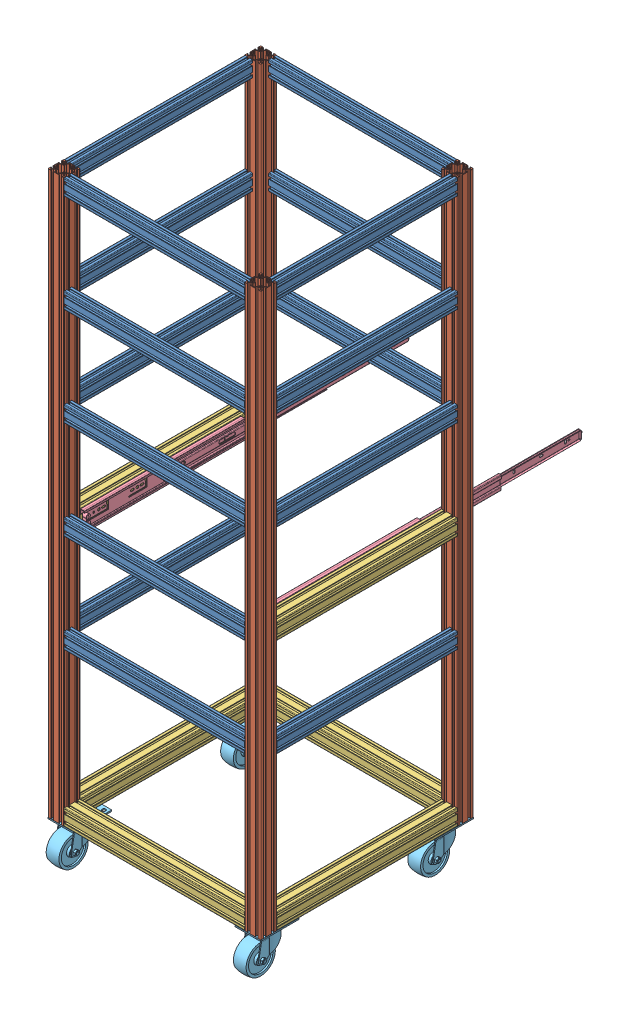
SolidWorks assembly Frame V4, configuration Default. Lengths in mm.
Overall size (530 1495.25 868.67).
34 component instances, 5 part files, 61 mates.
Components (placement in the parent):
- Frame V3 Front_or_Back-1: Frame V3 Front_or_Back [Default] at (-126.3106 303.3726 1707.2815) size (40 1400 530)
  - 20_2040_450_CL-1: 20_2040_450_CL [Default] at (841.1716 1609.6814 362.4928) size (20 40 450)
  - 20_2040_450_CL-2: 20_2040_450_CL [Default] at (841.1716 1364.9814 362.4928) size (20 40 450)
  - 20_2040_450_CL-3: 20_2040_450_CL [Default] at (841.1716 1120.2814 362.4928) size (20 40 450)
  - 20_4040_1400_CL-1: 20_4040_1400_CL [Default] at (851.1716 239.6814 372.4928) x (1 0 0) z (0 -1 0) size (40 40 1400)
  - 20_4040_1400_CL-2: 20_4040_1400_CL [Default] at (851.1716 239.6814 -117.5072) x (1 0 0) z (0 -1 0) size (40 40 1400)
  - 20_2040_450_CL-5: 20_2040_450_CL [Default] at (841.1716 630.8814 362.4928) size (20 40 450)
  - 20_4040_450_CL-1: 20_4040_450_CL [Default] at (851.1716 875.5814 362.4928) size (40 40 450)
- Frame V3 Front_or_Back-2: Frame V3 Front_or_Back [Default] at (2066.0326 303.3726 1982.2671) x (-1 0 0) z (0 0 -1) size (40 1400 530)
  - 20_2040_450_CL-1: 20_2040_450_CL [Default] at (841.1716 1609.6814 362.4928) size (20 40 450)
  - 20_2040_450_CL-2: 20_2040_450_CL [Default] at (841.1716 1364.9814 362.4928) size (20 40 450)
  - 20_2040_450_CL-3: 20_2040_450_CL [Default] at (841.1716 1120.2814 362.4928) size (20 40 450)
  - 20_4040_1400_CL-1: 20_4040_1400_CL [Default] at (851.1716 239.6814 372.4928) x (1 0 0) z (0 -1 0) size (40 40 1400)
  - 20_4040_1400_CL-2: 20_4040_1400_CL [Default] at (851.1716 239.6814 -117.5072) x (1 0 0) z (0 -1 0) size (40 40 1400)
  - 20_2040_450_CL-5: 20_2040_450_CL [Default] at (841.1716 630.8814 362.4928) size (20 40 450)
  - 20_4040_450_CL-1: 20_4040_450_CL [Default] at (851.1716 875.5814 362.4928) size (40 40 450)
- 20_2040_450_CL-1: 20_2040_450_CL [Default] at (1194.861 1913.054 2099.7743) x (0 0 -1) z (1 0 0) size (20 40 450)
- 20_2040_450_CL-2: 20_2040_450_CL [Default] at (1194.861 1913.054 1589.7743) x (0 0 -1) z (1 0 0) size (20 40 450)
- 20_4040_450_CL-1: 20_4040_450_CL [Default] at (1214.861 553.054 2069.7743) size (40 40 450)
- 20_4040_450_CL-2: 20_4040_450_CL [Default] at (724.861 553.054 2069.7743) size (40 40 450)
- 20_2040_450_CL-3: 20_2040_450_CL [Default] at (1194.861 1668.354 2099.7743) x (0 0 -1) z (1 0 0) size (20 40 450)
- 20_2040_450_CL-4: 20_2040_450_CL [Default] at (1194.861 1423.654 2099.7743) x (0 0 -1) z (1 0 0) size (20 40 450)
- 20_4040_450_CL-3: 20_4040_450_CL [Default] at (1194.861 553.054 2089.7743) x (0 0 -1) z (1 0 0) size (40 40 450)
- 20_4040_450_CL-4: 20_4040_450_CL [Default] at (1194.861 553.054 1599.7743) x (0 0 -1) z (1 0 0) size (40 40 450)
- 20_2040_450_CL-5: 20_2040_450_CL [Default] at (1194.861 1178.954 2099.7743) x (0 0 -1) z (1 0 0) size (20 40 450)
- 20_2040_450_CL-6: 20_2040_450_CL [Default] at (1194.861 934.254 2099.7743) x (0 0 -1) z (1 0 0) size (20 40 450)
- 20_2040_450_CL-7: 20_2040_450_CL [Default] at (1194.861 1668.354 1589.7743) x (0 0 -1) z (1 0 0) size (20 40 450)
- 20_2040_450_CL-8: 20_2040_450_CL [Default] at (1194.861 1423.654 1589.7743) x (0 0 -1) z (1 0 0) size (20 40 450)
- 11435A14_Steel Drawer Slides-3: 11435A14_Steel Drawer Slides [11435A14] at (1187.9155 1186.2842 1663.3743) x (-0.999657 0.026177 0) z (0 0 1) size (12.7 45.64 806.45)
- 11435A14_Steel Drawer Slides-4: 11435A14_Steel Drawer Slides [11435A14] at (751.8049 1186.2842 1663.3743) x (0.999657 0.026177 0) z (0 0 1) size (12.7 45.64 806.45)
- 2358T21_Static-Control Plate Caster-1: 2358T21_Static-Control Plate Caster [2358T21] at (736.611 485.904 2093.8993) size (63.5 95.25 117.47)
- 2358T21_Static-Control Plate Caster-2: 2358T21_Static-Control Plate Caster [2358T21] at (1203.111 485.904 2093.8993) size (63.5 95.25 117.47)
- 2358T21_Static-Control Plate Caster-3: 2358T21_Static-Control Plate Caster [2358T21] at (1203.111 485.904 1659.1493) size (63.5 95.25 117.47)
- 2358T21_Static-Control Plate Caster-4: 2358T21_Static-Control Plate Caster [2358T21] at (736.611 485.904 1659.1493) size (63.5 95.25 117.47)
Mates (geometry in assembly coordinates):
- Coincident16: coincident anti-aligned: plane of Frame V3 Front_or_Back-1/40_4040_1400_CL-1 through (946.4642 1867.0428 2134.8899) normal (1 0 0); plane of 20_2040_450_CL-1 through (744.861 1941.554 2108.2743) normal (-1 0 0)
- Coincident17: coincident aligned: plane of Frame V3 Front_or_Back-1/40_4040_1400_CL-1 through (943.2942 1867.0428 2149.1994) normal (0 0 1); plane of 20_2040_450_CL-1 through (744.861 1929.916 2109.7743) normal (0 0 1)
- Coincident18: coincident aligned: plane of Frame V3 Front_or_Back-1/40_4040_1400_CL-1 through (909.6342 1867.0428 2146.0294) normal (0 1 0); plane of 20_2040_450_CL-1 through (744.861 1943.054 2102.9123) normal (0 1 0)
- Coincident21: coincident: plane of Frame V3 Front_or_Back-1/40_4040_1400_CL-2 through (946.4642 1867.0428 1622.3694) normal (1 0 0); plane of 20_2040_450_CL-2 through (744.861 1941.554 1598.2743) normal (-1 0 0)
- Coincident22: coincident: plane of Frame V3 Front_or_Back-1/40_4040_1400_CL-2 through (932.1546 1867.0428 1619.1994) normal (0 0 -1); plane of 20_2040_450_CL-2 through (744.861 1916.192 1579.7743) normal (0 0 -1)
- Coincident23: coincident aligned: plane of Frame V3 Front_or_Back-2/40_4040_1400_CL-1 through (1433.2942 1867.0428 1622.3694) normal (0 1 0); plane of 20_2040_450_CL-2 through (744.861 1943.054 1581.2743) normal (0 1 0)
- Coincident24: coincident anti-aligned: plane of Frame V3 Front_or_Back-1/20_4040_1400_CL-1 through (744.861 1943.054 2082.9123) normal (1 0 0); plane of 20_2040_450_CL-1 through (744.861 1941.554 2108.2743) normal (-1 0 0)
- Coincident25: coincident aligned: plane of Frame V3 Front_or_Back-1/20_4040_1400_CL-1 through (731.723 1943.054 2109.7743) normal (0 0 1); plane of 20_2040_450_CL-1 through (744.861 1929.916 2109.7743) normal (0 0 1)
- Coincident26: coincident aligned: plane of Frame V3 Front_or_Back-1/20_4040_1400_CL-1 through (706.361 1943.054 2108.2743) normal (0 1 0); plane of 20_2040_450_CL-1 through (744.861 1943.054 2102.9123) normal (0 1 0)
- Coincident27: coincident anti-aligned: plane of Frame V3 Front_or_Back-1/20_4040_1400_CL-2 through (744.861 1943.054 1592.9123) normal (1 0 0); plane of 20_2040_450_CL-2 through (744.861 1941.554 1598.2743) normal (-1 0 0)
- Coincident28: coincident aligned: plane of Frame V3 Front_or_Back-1/20_4040_1400_CL-2 through (717.999 1943.054 1579.7743) normal (0 0 -1); plane of 20_2040_450_CL-2 through (744.861 1916.192 1579.7743) normal (0 0 -1)
- Coincident29: coincident aligned: plane of Frame V3 Front_or_Back-1/20_4040_1400_CL-2 through (706.361 1943.054 1618.2743) normal (0 1 0); plane of 20_2040_450_CL-2 through (744.861 1943.054 1581.2743) normal (0 1 0)
- Coincident30: coincident anti-aligned: plane of Frame V3 Front_or_Back-2/20_4040_1400_CL-2 through (1194.861 1943.054 2096.6363) normal (-1 0 0); plane of 20_2040_450_CL-1 through (1194.861 1941.554 2108.2743) normal (1 0 0)
- Coincident31: coincident aligned: plane of Frame V3 Front_or_Back-2/20_4040_1400_CL-2 through (1233.361 1943.054 2071.2743) normal (0 1 0); plane of 20_2040_450_CL-1 through (744.861 1943.054 2102.9123) normal (0 1 0)
- Coincident32: coincident aligned: plane of Frame V3 Front_or_Back-2/20_4040_1400_CL-2 through (1201.723 1943.054 2109.7743) normal (0 0 1); plane of 20_2040_450_CL-1 through (744.861 1929.916 2109.7743) normal (0 0 1)
- Coincident34: coincident anti-aligned: plane of Frame V3 Front_or_Back-2/20_4040_1400_CL-2 through (1207.999 1943.054 2069.7743) normal (0 0 -1); plane of 20_4040_450_CL-1 through (1196.361 581.554 2069.7743) normal (0 0 1)
- Coincident35: coincident aligned: plane of Frame V3 Front_or_Back-2/20_4040_1400_CL-2 through (1234.861 1943.054 2082.9123) normal (1 0 0); plane of 20_4040_450_CL-1 through (1234.861 556.192 1619.7743) normal (1 0 0)
- Coincident36: coincident aligned: plane of Frame V3 Front_or_Back-2/20_4040_1400_CL-2 through (1233.361 543.054 2071.2743) normal (0 -1 0); plane of 20_4040_450_CL-1 through (1207.999 543.054 1619.7743) normal (0 -1 0)
- Coincident37: coincident anti-aligned: plane of Frame V3 Front_or_Back-1/20_4040_1400_CL-1 through (717.999 1943.054 2069.7743) normal (0 0 -1); plane of 20_4040_450_CL-2 through (706.361 581.554 2069.7743) normal (0 0 1)
- Coincident38: coincident aligned: plane of Frame V3 Front_or_Back-1/20_4040_1400_CL-1 through (704.861 1943.054 2096.6363) normal (-1 0 0); plane of 20_4040_450_CL-2 through (704.861 569.916 1619.7743) normal (-1 0 0)
- Coincident39: coincident aligned: plane of Frame V3 Front_or_Back-1/20_4040_1400_CL-1 through (706.361 543.054 2108.2743) normal (0 -1 0); plane of 20_4040_450_CL-2 through (717.999 543.054 1619.7743) normal (0 -1 0)
- Coincident40: coincident anti-aligned: plane of Frame V3 Front_or_Back-1/20_4040_1400_CL-1 through (744.861 1943.054 2082.9123) normal (1 0 0); plane of 20_2040_450_CL-3 through (744.861 1696.854 2108.2743) normal (-1 0 0)
- Coincident41: coincident aligned: plane of Frame V3 Front_or_Back-1/20_4040_1400_CL-1 through (731.723 1943.054 2109.7743) normal (0 0 1); plane of 20_2040_450_CL-3 through (744.861 1685.216 2109.7743) normal (0 0 1)
- Distance1: distance = 204.7 mm anti-aligned: plane of 20_2040_450_CL-3 through (744.861 1698.354 2102.9123) normal (0 1 0); plane of 20_2040_450_CL-1 through (744.861 1903.054 2108.2743) normal (0 -1 0)
- Coincident43: coincident anti-aligned: plane of Frame V3 Front_or_Back-1/20_4040_1400_CL-1 through (744.861 1943.054 2082.9123) normal (1 0 0); plane of 20_2040_450_CL-4 through (744.861 1452.154 2108.2743) normal (-1 0 0)
- Coincident44: coincident aligned: plane of Frame V3 Front_or_Back-1/20_4040_1400_CL-1 through (731.723 1943.054 2109.7743) normal (0 0 1); plane of 20_2040_450_CL-4 through (744.861 1440.516 2109.7743) normal (0 0 1)
- Distance2: distance = 204.7 mm anti-aligned: plane of 20_2040_450_CL-4 through (744.861 1453.654 2102.9123) normal (0 1 0); plane of 20_2040_450_CL-3 through (744.861 1658.354 2108.2743) normal (0 -1 0)
- Coincident46: coincident anti-aligned: plane of Frame V3 Front_or_Back-1/20_4040_1400_CL-1 through (744.861 1943.054 2082.9123) normal (1 0 0); plane of 20_4040_450_CL-3 through (744.861 581.554 2108.2743) normal (-1 0 0)
- Coincident47: coincident aligned: plane of Frame V3 Front_or_Back-1/20_4040_1400_CL-1 through (731.723 1943.054 2109.7743) normal (0 0 1); plane of 20_4040_450_CL-3 through (744.861 569.916 2109.7743) normal (0 0 1)
- Coincident48: coincident aligned: plane of Frame V3 Front_or_Back-1/20_4040_1400_CL-1 through (706.361 543.054 2108.2743) normal (0 -1 0); plane of 20_4040_450_CL-3 through (744.861 543.054 2096.6363) normal (0 -1 0)
- Coincident49: coincident anti-aligned: plane of Frame V3 Front_or_Back-2/20_4040_1400_CL-1 through (1194.861 1943.054 1606.6363) normal (-1 0 0); plane of 20_4040_450_CL-4 through (1194.861 581.554 1618.2743) normal (1 0 0)
- Coincident50: coincident aligned: plane of Frame V3 Front_or_Back-2/20_4040_1400_CL-1 through (1207.999 1943.054 1579.7743) normal (0 0 -1); plane of 20_4040_450_CL-4 through (744.861 556.192 1579.7743) normal (0 0 -1)
- Coincident51: coincident aligned: plane of Frame V3 Front_or_Back-2/20_4040_1400_CL-1 through (1233.361 543.054 1581.2743) normal (0 -1 0); plane of 20_4040_450_CL-4 through (744.861 543.054 1606.6363) normal (0 -1 0)
- Coincident52: coincident anti-aligned: plane of Frame V3 Front_or_Back-1/20_4040_1400_CL-1 through (744.861 1943.054 2082.9123) normal (1 0 0); plane of 20_2040_450_CL-5 through (744.861 1207.454 2108.2743) normal (-1 0 0)
- Coincident53: coincident aligned: plane of Frame V3 Front_or_Back-1/20_4040_1400_CL-1 through (731.723 1943.054 2109.7743) normal (0 0 1); plane of 20_2040_450_CL-5 through (744.861 1195.816 2109.7743) normal (0 0 1)
- Distance3: distance = 204.7 mm anti-aligned: plane of 20_2040_450_CL-5 through (744.861 1208.954 2102.9123) normal (0 1 0); plane of 20_2040_450_CL-4 through (744.861 1413.654 2096.6363) normal (0 -1 0)
- Coincident55: coincident anti-aligned: plane of Frame V3 Front_or_Back-1/20_4040_1400_CL-1 through (744.861 1943.054 2082.9123) normal (1 0 0); plane of 20_2040_450_CL-6 through (744.861 962.754 2108.2743) normal (-1 0 0)
- Coincident56: coincident aligned: plane of Frame V3 Front_or_Back-1/20_4040_1400_CL-1 through (731.723 1943.054 2109.7743) normal (0 0 1); plane of 20_2040_450_CL-6 through (744.861 951.116 2109.7743) normal (0 0 1)
- Distance4: distance = 204.7 mm anti-aligned: plane of 20_2040_450_CL-6 through (744.861 964.254 2102.9123) normal (0 1 0); plane of 20_2040_450_CL-5 through (744.861 1168.954 2108.2743) normal (0 -1 0)
- Coincident58: coincident anti-aligned: plane of Frame V3 Front_or_Back-2/20_4040_1400_CL-1 through (1194.861 1943.054 1606.6363) normal (-1 0 0); plane of 20_2040_450_CL-7 through (1194.861 1696.854 1598.2743) normal (1 0 0)
- Coincident59: coincident aligned: plane of Frame V3 Front_or_Back-2/20_4040_1400_CL-1 through (1207.999 1943.054 1579.7743) normal (0 0 -1); plane of 20_2040_450_CL-7 through (744.861 1671.492 1579.7743) normal (0 0 -1)
- Distance5: distance = 204.7 mm anti-aligned: plane of 20_2040_450_CL-7 through (744.861 1698.354 1592.9123) normal (0 1 0); plane of 20_2040_450_CL-2 through (744.861 1903.054 1586.6363) normal (0 -1 0)
- Coincident62: coincident anti-aligned: plane of Frame V3 Front_or_Back-2/20_4040_1400_CL-1 through (1194.861 1943.054 1606.6363) normal (-1 0 0); plane of 20_2040_450_CL-8 through (1194.861 1452.154 1598.2743) normal (1 0 0)
- Coincident63: coincident aligned: plane of Frame V3 Front_or_Back-2/20_4040_1400_CL-1 through (1207.999 1943.054 1579.7743) normal (0 0 -1); plane of 20_2040_450_CL-8 through (744.861 1426.792 1579.7743) normal (0 0 -1)
- Distance6: distance = 204.7 mm anti-aligned: plane of 20_2040_450_CL-8 through (744.861 1453.654 1592.9123) normal (0 1 0); plane of 20_2040_450_CL-7 through (744.861 1658.354 1586.6363) normal (0 -1 0)
- Coincident74: coincident aligned: plane of Frame V3 Front_or_Back-2/20_4040_450_CL-1 through (1233.361 1207.454 2069.7743) normal (0 0 1); plane of 11435A14_Steel Drawer Slides-3 through (1183.2651 1164.4281 2069.7743) normal (0 0 1)
- Coincident80: coincident aligned: plane of Frame V3 Front_or_Back-2/20_4040_450_CL-1 through (1196.361 1208.954 2069.7743) normal (0 1 0); plane of 11435A14_Steel Drawer Slides-3 through (1193.9878 1208.954 2069.7743) normal (0 1 0)
- Coincident82: coincident aligned: plane of Frame V3 Front_or_Back-1/20_4040_450_CL-1 through (706.361 1207.454 2069.7743) normal (0 0 1); plane of 11435A14_Steel Drawer Slides-4 through (755.3051 1208.3537 2069.7743) normal (0 0 1)
- Coincident84: coincident aligned: plane of Frame V3 Front_or_Back-1/20_4040_450_CL-1 through (743.361 1208.954 1619.7743) normal (0 1 0); plane of 11435A14_Steel Drawer Slides-4 through (745.7325 1208.954 2069.7743) normal (0 1 0)
- Coincident85: coincident anti-aligned: plane of 20_4040_450_CL-2 through (717.999 543.054 1619.7743) normal (0 -1 0); plane of 2358T21_Static-Control Plate Caster-1 through (704.861 543.054 2014.5243) normal (0 1 0)
- Coincident86: coincident aligned: plane of 20_4040_450_CL-2 through (704.861 549.916 1619.7743) normal (-1 0 0); plane of 2358T21_Static-Control Plate Caster-1 through (704.861 539.879 2109.7743) normal (-1 0 0)
- Coincident87: coincident aligned: plane of Frame V3 Front_or_Back-1/20_4040_1400_CL-1 through (731.723 1943.054 2109.7743) normal (0 0 1); plane of 2358T21_Static-Control Plate Caster-1 through (704.861 539.879 2109.7743) normal (0 0 1)
- Coincident88: coincident anti-aligned: plane of 20_4040_450_CL-1 through (1207.999 543.054 1619.7743) normal (0 -1 0); plane of 2358T21_Static-Control Plate Caster-2 through (1171.361 543.054 2014.5243) normal (0 1 0)
- Coincident89: coincident aligned: plane of Frame V3 Front_or_Back-2/20_4040_1400_CL-2 through (1221.723 1943.054 2109.7743) normal (0 0 1); plane of 2358T21_Static-Control Plate Caster-2 through (1171.361 539.879 2109.7743) normal (0 0 1)
- Coincident90: coincident aligned: plane of 20_4040_450_CL-1 through (1234.861 544.554 1619.7743) normal (1 0 0); plane of 2358T21_Static-Control Plate Caster-2 through (1234.861 539.879 2109.7743) normal (1 0 0)
- Coincident91: coincident anti-aligned: plane of 20_4040_450_CL-1 through (1207.999 543.054 1619.7743) normal (0 -1 0); plane of 2358T21_Static-Control Plate Caster-3 through (1171.361 543.054 1579.7743) normal (0 1 0)
- Coincident92: coincident aligned: plane of 20_4040_450_CL-1 through (1234.861 544.554 1619.7743) normal (1 0 0); plane of 2358T21_Static-Control Plate Caster-3 through (1234.861 539.879 1675.0243) normal (1 0 0)
- Coincident93: coincident aligned: plane of Frame V3 Front_or_Back-2/20_4040_1400_CL-1 through (1207.999 1943.054 1579.7743) normal (0 0 -1); plane of 2358T21_Static-Control Plate Caster-3 through (1171.361 539.879 1579.7743) normal (0 0 -1)
- Coincident94: coincident anti-aligned: plane of 20_4040_450_CL-4 through (744.861 543.054 1606.6363) normal (0 -1 0); plane of 2358T21_Static-Control Plate Caster-4 through (704.861 543.054 1579.7743) normal (0 1 0)
- Coincident95: coincident aligned: plane of Frame V3 Front_or_Back-1/20_4040_1400_CL-2 through (704.861 1943.054 1606.6363) normal (-1 0 0); plane of 2358T21_Static-Control Plate Caster-4 through (704.861 539.879 1675.0243) normal (-1 0 0)
- Coincident96: coincident aligned: plane of Frame V3 Front_or_Back-1/20_4040_1400_CL-2 through (717.999 1943.054 1579.7743) normal (0 0 -1); plane of 2358T21_Static-Control Plate Caster-4 through (704.861 539.879 1579.7743) normal (0 0 -1)
